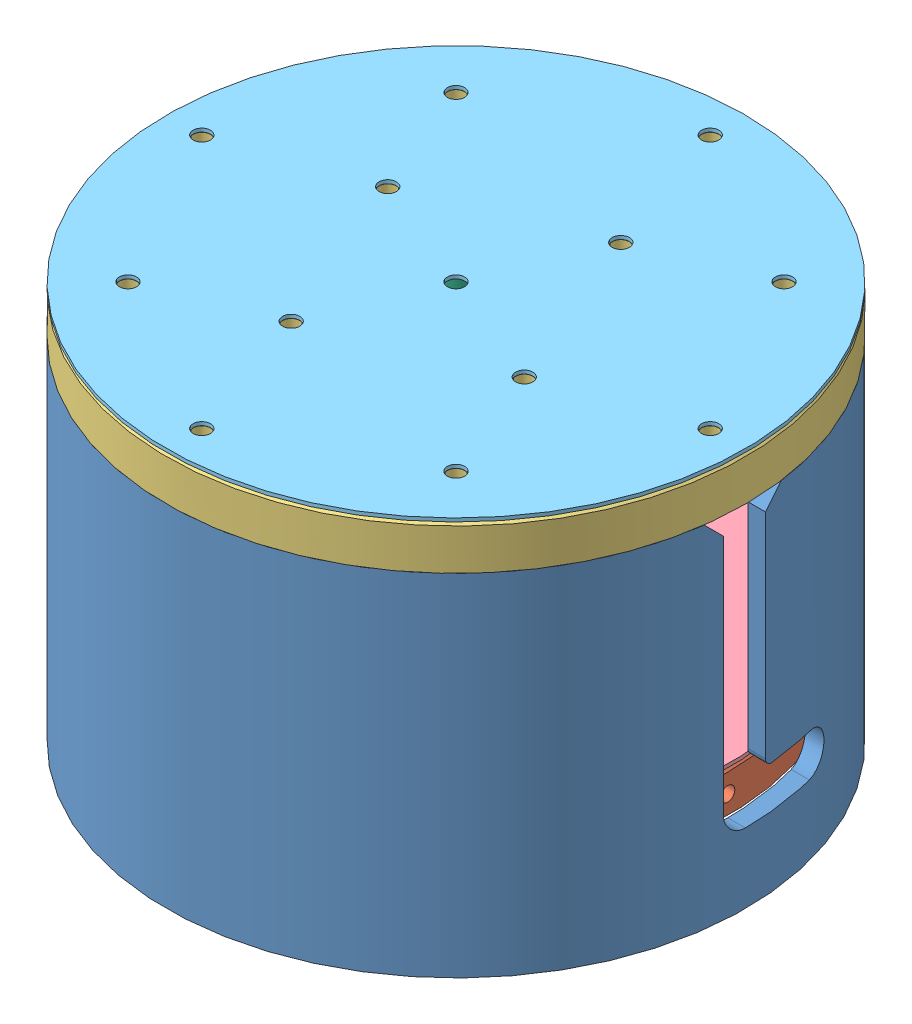
SolidWorks assembly FullFEAAssembly, configuration Default. Lengths in mm.
Overall size (215.71 146.1 215.71).
10 component instances, 7 part files, 23 mates.
Components (placement in the parent):
- payring3FEA-1: payring3FEA [Default] at origin size (165.1 100 165.1)
- payring1V2FEA-1: payring1V2FEA [Default] at (0 32.27 0) x (0.92388 0 0.382683) z (0.382683 0 -0.92388) size (155.1 13.16 155.1)
- payring2FEA-1: payring2FEA [Default] at (0 112.7 0) x (0.92388 0 -0.382683) z (-0.382683 0 -0.92388) size (165.1 12.7 165.1)
- sealing plateFEA-1: sealing plateFEA [Default] at (0 33.27 0) x (0.92388 0 0.382683) z (0.382683 0 -0.92388) size (155.1 1 155.1)
- sealing plate2FEA-1: sealing plate2FEA [Default] at (0 112.7 0) x (0.382683 0 0.92388) z (-0.92388 0 0.382683) size (165.1 1 165.1)
- Upper_rod2FEA-1: Upper_rod2FEA [Default] at (46.8105 33.27 46.8105) x (0.837169 0 0.546944) z (0 1 0) size (12.8 12.8 66.73)
- Upper_rod2FEA-2: Upper_rod2FEA [Default] at (46.8105 33.27 -46.8105) x (0.837169 0 0.546944) z (0 1 0) size (12.8 12.8 66.73)
- Upper_rod2FEA-3: Upper_rod2FEA [Default] at (-46.8105 33.27 46.8105) x (0.837169 0 0.546944) z (0 1 0) size (12.8 12.8 66.73)
- Upper_rod2FEA-4: Upper_rod2FEA [Default] at (-46.8105 33.27 -46.8105) x (0.837169 0 0.546944) z (0 1 0) size (12.8 12.8 66.73)
- eyeboltFEA-1: eyeboltFEA [Default] at (0 32.27 0) x (0.381402 0 0.924409) z (0.924409 0 -0.381402) size (15.53 64.67 49.98)
Mates (geometry in assembly coordinates):
- Concentric1: concentric anti-aligned: cylinder of payring1V2FEA-1 through (-53.3806 19.57 -39.153) axis (0 -1 0) radius 2.4003; cylinder of Upper_rod2FEA-4 through (-53.3806 100 -39.153) axis (0 1 0) radius 1.8986
- Concentric3: concentric anti-aligned: cylinder of payring1V2FEA-1 through (39.153 19.57 -53.3806) axis (0 -1 0) radius 2.4003; cylinder of Upper_rod2FEA-2 through (39.153 100 -53.3806) axis (0 1 0) radius 1.8986
- Concentric4: concentric anti-aligned: cylinder of payring1V2FEA-1 through (-39.153 19.57 53.3806) axis (0 -1 0) radius 2.4003; cylinder of Upper_rod2FEA-3 through (-39.153 100 53.3806) axis (0 1 0) radius 1.8986
- Concentric5: concentric anti-aligned: cylinder of payring1V2FEA-1 through (53.3806 19.57 39.153) axis (0 -1 0) radius 2.4003; cylinder of Upper_rod2FEA-1 through (53.3806 100 39.153) axis (0 1 0) radius 1.8986
- Concentric6: concentric aligned: cylinder of payring1V2FEA-1 through (-53.3806 19.57 -39.153) axis (0 -1 0) radius 2.4003; cylinder of sealing plateFEA-1 through (-53.3806 32.27 -39.153) axis (0 -1 0) radius 2.4574
- Concentric7: concentric aligned: cylinder of payring1V2FEA-1 through (-39.153 19.57 53.3806) axis (0 -1 0) radius 2.4003; cylinder of sealing plateFEA-1 through (-39.153 32.27 53.3806) axis (0 -1 0) radius 2.4574
- Coincident5: coincident anti-aligned: plane of payring1V2FEA-1 through (0 32.27 0) normal (0 1 0); plane of sealing plateFEA-1 through (18.4442 32.27 -75.3247) normal (0 -1 0)
- Coincident6: coincident anti-aligned: plane of sealing plateFEA-1 through (0 33.27 0) normal (0 1 0); plane of Upper_rod2FEA-3 through (-39.153 33.27 53.3806) normal (0 -1 0)
- Coincident7: coincident anti-aligned: plane of sealing plateFEA-1 through (0 33.27 0) normal (0 1 0); plane of Upper_rod2FEA-1 through (53.3806 33.27 39.153) normal (0 -1 0)
- Coincident8: coincident anti-aligned: plane of sealing plateFEA-1 through (0 33.27 0) normal (0 1 0); plane of Upper_rod2FEA-4 through (-53.3806 33.27 -39.153) normal (0 -1 0)
- Coincident9: coincident anti-aligned: plane of sealing plateFEA-1 through (0 33.27 0) normal (0 1 0); plane of Upper_rod2FEA-2 through (39.153 33.27 -53.3806) normal (0 -1 0)
- Coincident11: coincident anti-aligned: plane of payring2FEA-1 through (0 112.7 0) normal (0 1 0); plane of sealing plate2FEA-1 through (0 112.7 0) normal (0 -1 0)
- Concentric12: concentric anti-aligned: cylinder of payring2FEA-1 through (71.7073 100 -11.0254) axis (0 -1 0) radius 2.4003; cylinder of sealing plate2FEA-1 through (71.7073 113.7 -11.0254) axis (0 1 0) radius 2.4574
- Concentric13: concentric anti-aligned: cylinder of payring2FEA-1 through (53.3806 100 39.153) axis (0 -1 0) radius 2.4003; cylinder of sealing plate2FEA-1 through (53.3806 113.7 39.153) axis (0 1 0) radius 2.4574
- Concentric14: concentric anti-aligned: cylinder of payring2FEA-1 through (34.967 100 8.5621) axis (0 -1 0) radius 2.4003; cylinder of sealing plate2FEA-1 through (34.967 113.7 8.5621) axis (0 1 0) radius 2.4574
- Concentric15: concentric anti-aligned: cylinder of payring2FEA-1 through (39.153 100 -53.3806) axis (0 -1 0) radius 2.4003; cylinder of Upper_rod2FEA-2 through (39.153 100 -53.3806) axis (0 1 0) radius 1.8986
- Concentric16: concentric anti-aligned: cylinder of payring2FEA-1 through (-53.3806 100 -39.153) axis (0 -1 0) radius 2.4003; cylinder of Upper_rod2FEA-4 through (-53.3806 100 -39.153) axis (0 1 0) radius 1.8986
- Coincident12: coincident anti-aligned: plane of payring2FEA-1 through (-42.8138 100 -70.5796) normal (0 -1 0); plane of Upper_rod2FEA-4 through (-53.3806 100 -39.153) normal (0 1 0)
- Concentric18: concentric aligned: cylinder of payring1V2FEA-1 through (0 32.37 0) axis (0 -1 0) radius 4.765; cylinder of eyeboltFEA-1 through (0 13.57 0) axis (0 -1 0) radius 4.765
- Coincident15: coincident anti-aligned: plane of payring1V2FEA-1 through (18.4442 19.57 -75.3247) normal (0 -1 0); plane of eyeboltFEA-1 through (1.8174 19.57 4.4048) normal (0 1 0)
- Coincident18: coincident anti-aligned: plane of payring3FEA-1 through (0 100 82.55) normal (0 1 0); plane of payring2FEA-1 through (-42.8138 100 -70.5796) normal (0 -1 0)
- Concentric19: concentric anti-aligned: cylinder of payring3FEA-1 through (0 -5 0) axis (0 -1 0) radius 82.55; cylinder of payring2FEA-1 through (0 113.335 0) axis (0 1 0) radius 82.55
- Parallel2: parallel aligned: cylinder of payring3FEA-1 through (82.55 26 -21) axis (-1 0 0) radius 6; cylinder of payring1V2FEA-1 through (0 25.92 0) axis (-1 0 0) radius 2.0447
